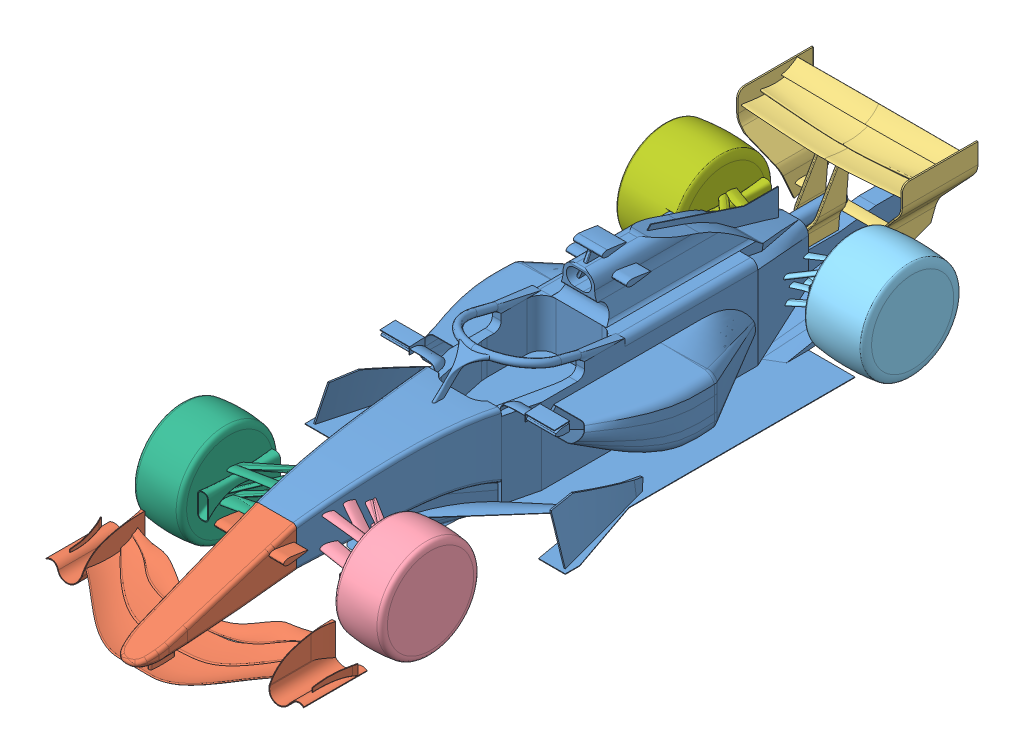
SolidWorks assembly My 2026 F1 Car, configuration Default. Lengths in mm.
Overall size (1806.42 1086.17 5446.68).
7 component instances, 7 part files, 20 mates.
Components (placement in the parent):
- Chassis-1: Chassis [Default] at origin size (1806.42 1058.99 4408.54)
- 2026 Front Wing_Optimising-1: 2026 Front Wing_Optimising [Design_2] at (144.6856 -121.2708 0) x (0 0 -1) z (1 0 0) size (1038.14 477.58 1804.96)
- F1 2026 Rear Wing-1: F1 2026 Rear Wing [Default] at (-205.4166 24.1734 -4299.5396) size (1150 628.71 721.01)
- Front Right-1: Front Right [Default] at (842.8387 78.0641 -385.9743) x (0 0 1) z (-1 0 0) size (775.4 705 792.1)
- Rear Right-3: Rear Right [Default] at (799.6928 81.2674 -3733.2115) x (0 0 1) z (-1 0 0) size (833.19 710 924.75)
- Front Left-1: Front Left [Default] at (-550.7836 78.0641 -385.9743) x (0 0 1) z (-1 0 0) size (768.84 705 792.1)
- Left Rear-1: Left Rear [Default] at (-507.6436 81.2674 -3733.2115) x (0 0 1) z (-1 0 0) size (844.85 710 924.76)
Mates (geometry in assembly coordinates):
- Coincident1: coincident aligned: line of Chassis-1 through (228.402 0 253.5688) axis (0 0 -1); line of 2026 Front Wing_Optimising-1 through (0 252.5186 0) axis (0 -1 0)
- Coincident2: coincident anti-aligned: line of Chassis-1 through (239.9067 264.5367 278.7292) axis (0 -1 0); line of 2026 Front Wing_Optimising-1 through (239.8969 24.7372 278.7292) axis (0 1 0)
- Coincident3: coincident anti-aligned: plane of Chassis-1 through (-812.9785 67.5834 0) normal (0 1 0); plane of F1 2026 Rear Wing-1 through (-205.4166 67.5834 -3899.5396) normal (0 -1 0)
- Width1: width aligned: plane of Chassis-1 through (203.1531 -194.4359 -3578.5244) normal (1 0 0); plane of Chassis-1 through (86.0136 -239.4359 -3578.5244) normal (-1 0 0); plane of F1 2026 Rear Wing-1 through (187.0834 24.1734 -3899.5396) normal (1 0 0); plane of F1 2026 Rear Wing-1 through (102.0834 24.1734 -3899.5396) normal (-1 0 0)
- Parallel2: parallel aligned: plane of 2026 Front Wing_Optimising-1 through (1038.9545 -92.6459 1038.1448) normal (1 0 0); plane of Front Right-1 through (1009.8387 78.0641 -508.9848) normal (1 0 0)
- Distance1: distance = 405 mm: plane of Chassis-1 through (742.8062 -239.4359 -936.8946) normal (0 1 0); line of Front Right-1 through (645.8387 165.5641 14.0257) axis (-1 0 0)
- Distance2: distance = 84.5349 mm: line of Front Right-1 through (675.8387 -8.9685 -313.8169) axis (-0.81253 0.14135 -0.565522); line of Chassis-1 through (919.7458 109.5641 -1136.6685) axis (-1 0 0)
- Distance3: distance = 29.1158 mm aligned: plane of Front Right-1 through (1009.8387 78.0641 -508.9848) normal (1 0 0); plane of 2026 Front Wing_Optimising-1 through (1038.9545 -92.6459 1038.1448) normal (1 0 0)
- Distance4: distance = 469.9968 mm: line of 2026 Front Wing_Optimising-1 through (819.6856 -125.1552 258.7993) axis (0 1 0); line of Front Right-1 through (675.8387 36.2392 -273.1131) axis (-0.823619 0.513228 -0.241348)
- Parallel9: parallel anti-aligned: line of Rear Right-3 through (1009.8428 436.2674 -3555.7115) axis (0 -1 0); line of assembly
- Parallel11: parallel aligned: plane of Front Right-1 through (1009.8387 78.0641 -508.9848) normal (1 0 0); plane of Rear Right-3 through (1009.8428 81.2674 -3555.7115) normal (1 0 0)
- Distance15: distance = 325.54 mm: plane of Rear Right-3 through (589.5428 81.2674 -3555.7115) normal (-1 0 0); line of Chassis-1 through (264.0028 214.8692 -3578.5281) axis (0 -1 0)
- Distance18: distance = 466.6159 mm: line of Rear Right-3 through (559.5428 181.2674 -3808.2115) axis (-1 0 0); line of F1 2026 Rear Wing-1 through (719.5834 647.8833 -3824.5396) axis (0 0 -1)
- Distance19: distance = 373.62 mm: line of Rear Right-3 through (559.5428 181.2674 -3333.2115) axis (-1 0 0); line of Chassis-1 through (547.8973 -190.4359 -3295.4155) axis (1 0 0)
- Concentric1: concentric aligned: circle of Front Right-1; circle of Front Left-1
- Concentric2: concentric aligned: circle of Rear Right-3; circle of Left Rear-1
- Coincident5: coincident aligned: line of Front Right-1 through (645.8387 165.5641 14.0257) axis (-1 0 0); line of Front Left-1 through (-338.7836 165.5641 14.0257) axis (-1 0 0)
- Coincident6: coincident aligned: line of Rear Right-3 through (559.5428 181.2674 -3333.2115) axis (-1 0 0); line of Left Rear-1 through (-252.4936 181.2674 -3333.2115) axis (-1 0 0)
- Distance21: distance = 529.81 mm aligned: plane of assembly through (146.0264 0 0) normal (1 0 0); plane of Front Left-1 through (-383.7836 78.0641 -508.9848) normal (1 0 0)
- Distance22: distance = 443.52 mm aligned: plane of assembly through (146.0264 0 0) normal (1 0 0); plane of Left Rear-1 through (-297.4936 81.2674 -3555.7115) normal (1 0 0)
